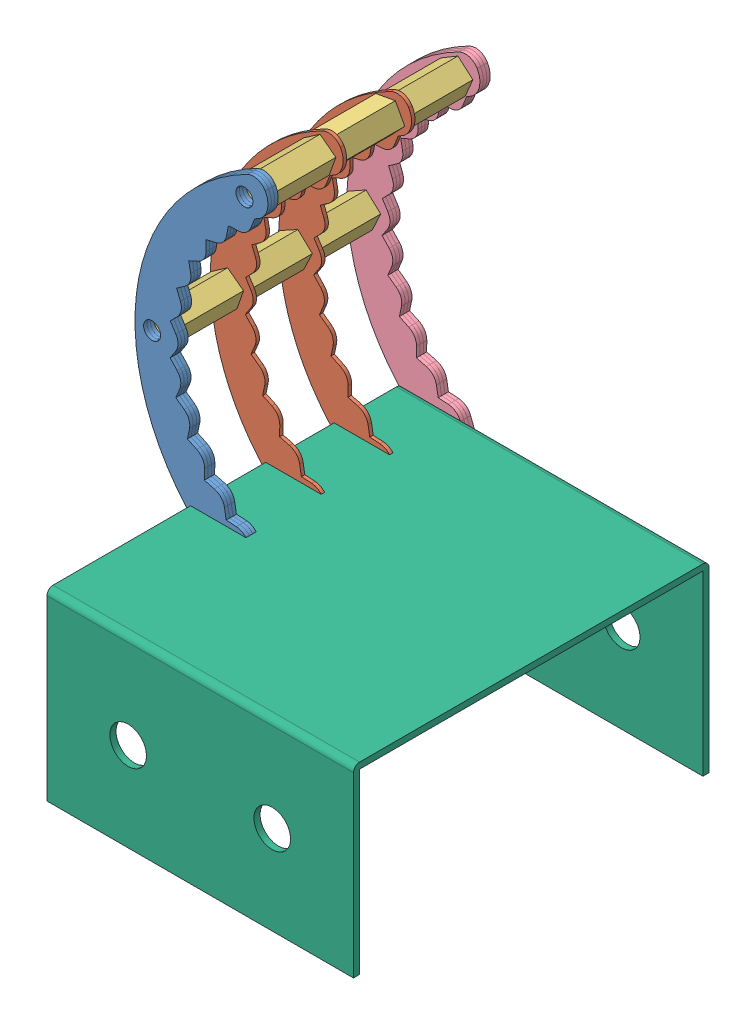
SolidWorks assembly RIGHT HAND, configuration Default. Lengths in mm.
Overall size (53.54 73.23 53.63).
18 component instances, 6 part files, 30 mates.
Components (placement in the parent):
- handle1-1: handle1 [Default] at (-7.5398 -35.6958 -27.6488) size (29.97 70.24 1.63)
- kiskac2-1: kiskac2 [Varsayılan] at (50.9968 46.7952 47.8369) size (19.45 53.92 0.5)
- araparca-1: araparca [Varsayılan] at (13.4048 24.2984 43.8369) x (0.977975 0.208721 0) z (0 0 1) size (4.68 4.59 9.5)
- araparca-2: araparca [Varsayılan] at (1.7149 46.7993 43.8369) x (0.9973 0.073437 0) z (0 0 1) size (4.68 4.59 9.5)
- araparca-3: araparca [Varsayılan] at (15.2145 70.4687 43.8369) x (0.997775 0.066667 0) z (0 0 1) size (4.68 4.59 9.5)
- araparca-4: araparca [Varsayılan] at (15.2145 70.4687 33.8369) x (-0.551736 0.834019 0) z (0 0 1) size (4.68 4.59 9.5)
- araparca-5: araparca [Varsayılan] at (1.7149 46.7993 33.8369) x (0.343925 0.938997 0) z (0 0 1) size (4.68 4.59 9.5)
- araparca-6: araparca [Varsayılan] at (13.4048 24.2984 33.8369) x (0.812716 0.582659 0) z (0 0 1) size (4.68 4.59 9.5)
- kiskac2-2: kiskac2 [Varsayılan] at (50.9968 46.7952 37.8369) size (19.45 53.92 0.5)
- araparca-13: araparca [Varsayılan] at (15.2145 70.4687 23.8369) size (4.68 4.59 9.5)
- araparca-14: araparca [Varsayılan] at (13.4048 24.2984 23.8369) size (4.68 4.59 9.5)
- araparca-15: araparca [Varsayılan] at (1.7149 46.7993 23.8369) x (0.999583 -0.028868 0) z (0 0 1) size (4.68 4.59 9.5)
- handle 2-1: handle 2 [Default] at (-16.5479 -33.7454 -75.777) size (32.9 73.09 1.63)
  - kiskac1-1: kiskac1 [Varsayılan] at (65.4233 86.2581 103.6139) size (25 65.23 0.5)
  - gear-3: gear [Default] at (35.7628 47.2729 102.4149) x (0 0 1) z (-0.933673 -0.358127 0) size (1.63 19.86 20.01)
  - kiskac1-2: kiskac1 [Varsayılan] at (65.4233 86.2581 103.1139) size (25 65.23 0.5)
  - kiskac1-3: kiskac1 [Varsayılan] at (65.4233 86.2581 102.6139) size (25 65.23 0.5)
- U-sac-1: U-sac [Varsayılan] at (54.7305 -1.773 25.5416) x (0 0 1) z (-1 0 0) size (52 26.9 44.83)
Mates (geometry in assembly coordinates):
- Concentric1: concentric anti-aligned: cylinder of handle1-1 through (15.2145 70.4687 59.5869) axis (0 0 -1) radius 1.25; circle of araparca-3
- Coincident2: coincident anti-aligned: plane of handle1-1 through (14.2809 67.7287 58.0869) normal (0 0 -1); plane of araparca-3 through (15.2145 70.4687 58.0869) normal (0 0 1)
- Concentric2: concentric anti-aligned: circle of handle1-1; cylinder of araparca-1 through (13.4048 24.2984 58.0869) axis (0 0 -1) radius 1.25
- Coincident5: coincident anti-aligned: plane of handle1-1 through (14.2809 67.7287 58.0869) normal (0 0 -1); plane of araparca-1 through (13.4048 24.2984 58.0869) normal (0 0 1)
- Coincident6: coincident anti-aligned: plane of handle1-1 through (14.2809 67.7287 58.0869) normal (0 0 -1); plane of araparca-2 through (1.7149 46.7993 58.0869) normal (0 0 1)
- Concentric3: concentric anti-aligned: circle of handle1-1; cylinder of araparca-2 through (1.7149 46.7993 58.0869) axis (0 0 -1) radius 1.25
- Concentric4: concentric aligned: circle of araparca-3; circle of kiskac2-1
- Coincident9: coincident anti-aligned: plane of araparca-3 through (15.2145 70.4687 48.5869) normal (0 0 -1); plane of kiskac2-1 through (14.2809 67.7287 48.5869) normal (0 0 1)
- Concentric5: concentric aligned: cylinder of araparca-2 through (1.7149 46.7993 58.0869) axis (0 0 -1) radius 1.25; cylinder of kiskac2-1 through (1.7149 46.7993 48.5869) axis (0 0 -1) radius 1.25
- Coincident10: coincident anti-aligned: plane of kiskac2-1 through (14.2809 67.7287 48.0869) normal (0 0 -1); plane of araparca-4 through (15.2145 70.4687 48.0869) normal (0 0 1)
- Coincident11: coincident anti-aligned: plane of kiskac2-1 through (14.2809 67.7287 48.0869) normal (0 0 -1); plane of araparca-5 through (1.7149 46.7993 48.0869) normal (0 0 1)
- Coincident12: coincident anti-aligned: plane of kiskac2-1 through (14.2809 67.7287 48.0869) normal (0 0 -1); plane of araparca-6 through (13.4048 24.2984 48.0869) normal (0 0 1)
- Coincident13: coincident anti-aligned: cylinder of kiskac2-1 through (15.2145 70.4687 48.5869) axis (0 0 -1) radius 1.25; circle of araparca-4
- Concentric6: concentric aligned: circle of kiskac2-1; circle of araparca-5
- Concentric7: concentric aligned: cylinder of araparca-1 through (13.4048 24.2984 58.0869) axis (0 0 -1) radius 1.25; cylinder of araparca-6 through (13.4048 24.2984 48.0869) axis (0 0 -1) radius 1.25
- Coincident15: coincident anti-aligned: plane of araparca-4 through (15.2145 70.4687 38.5869) normal (0 0 -1); plane of kiskac2-2 through (14.2809 67.7287 38.5869) normal (0 0 1)
- Concentric8: concentric anti-aligned: cylinder of araparca-4 through (15.2145 70.4687 48.0869) axis (0 0 -1) radius 1.25; circle of kiskac2-2
- Concentric9: concentric anti-aligned: cylinder of araparca-5 through (1.7149 46.7993 48.0869) axis (0 0 -1) radius 1.25; circle of kiskac2-2
- Concentric10: concentric anti-aligned: cylinder of araparca-6 through (13.4048 24.2984 48.0869) axis (0 0 -1) radius 1.25; circle of kiskac2-2
- Coincident19: coincident anti-aligned: plane of kiskac2-2 through (14.2809 67.7287 38.0869) normal (0 0 -1); plane of araparca-13 through (15.2145 70.4687 38.0869) normal (0 0 1)
- Concentric11: concentric anti-aligned: circle of kiskac2-2; cylinder of araparca-13 through (15.2145 70.4687 38.0869) axis (0 0 -1) radius 1.25
- Concentric12: concentric anti-aligned: circle of kiskac2-2; cylinder of araparca-15 through (1.7149 46.7993 38.0869) axis (0 0 -1) radius 1.25
- Coincident24: coincident anti-aligned: plane of kiskac2-2 through (14.2809 67.7287 38.0869) normal (0 0 -1); plane of araparca-15 through (1.7149 46.7993 38.0869) normal (0 0 1)
- Coincident25: coincident anti-aligned: plane of kiskac2-2 through (14.2809 67.7287 38.0869) normal (0 0 -1); plane of araparca-14 through (13.4048 24.2984 38.0869) normal (0 0 1)
- Concentric13: concentric aligned: cylinder of araparca-6 through (13.4048 24.2984 48.0869) axis (0 0 -1) radius 1.25; cylinder of araparca-14 through (13.4048 24.2984 38.0869) axis (0 0 -1) radius 1.25
- Coincident26: coincident anti-aligned: plane of araparca-14 through (13.4048 24.2984 28.5869) normal (0 0 -1); plane of handle 2-1/kiskac1-1 through (14.2809 67.7287 28.5869) normal (0 0 1)
- Concentric14: concentric anti-aligned: cylinder of araparca-14 through (13.4048 24.2984 38.0869) axis (0 0 -1) radius 1.25; circle of handle 2-1/kiskac1-3
- Concentric16: concentric aligned: cylinder of araparca-13 through (15.2145 70.4687 38.0869) axis (0 0 -1) radius 1.25; cylinder of handle 2-1/kiskac1-3 through (15.2145 70.4687 27.5869) axis (0 0 -1) radius 1.25
- Coincident30: coincident: plane of handle 2-1/gear-3 through (32.8611 5.8813 28.5869) normal (0 0 1); plane of U-sac-1 through (7.3356 0.5275 28.5869) normal (0 0 -1)
- Concentric17: concentric aligned: circle of handle 2-1/kiskac1-3; circle of U-sac-1
